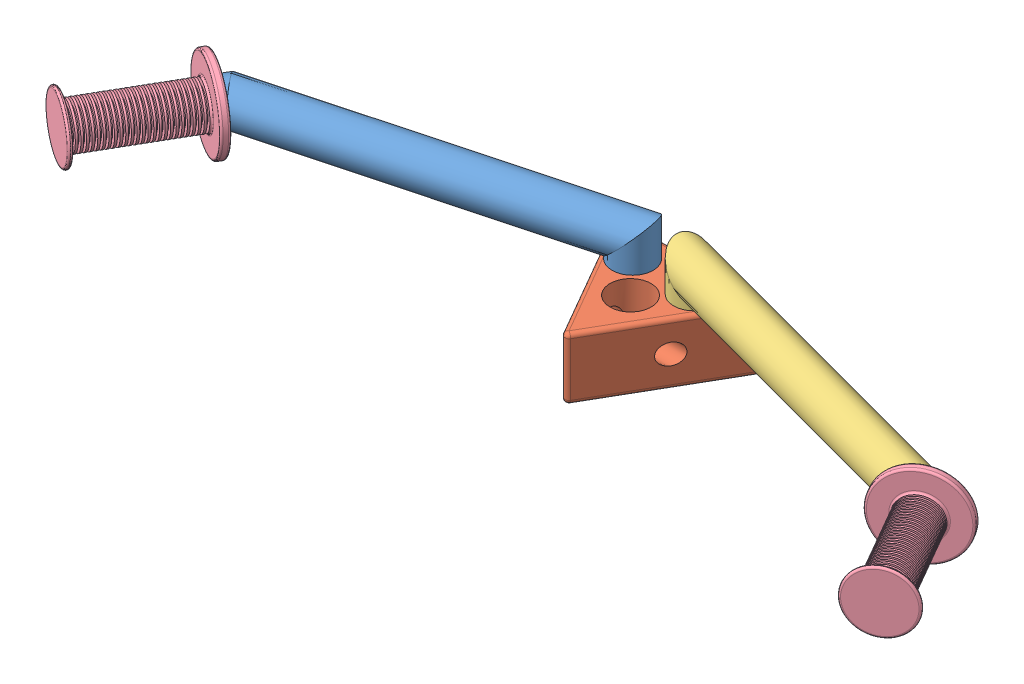
SolidWorks assembly stuur, configuration Default. Lengths in mm.
Overall size (435.74 60.06 120.1).
5 component instances, 4 part files, 8 mates.
Components (placement in the parent):
- stuurbuis1-2: stuurbuis1 [Default] at (-32.5291 -26.394 40.1826) x (-0.965926 0 0.258819) z (-0.258819 0 -0.965926) size (215.96 50 55.96)
- stuur-tussenstuk-1: stuur-tussenstuk [Default] at (-17.5291 -26.394 90.1345) size (72.07 30.12 62.95)
- stuurbuis2-1: stuurbuis2 [Default] at (-2.5291 -26.394 40.1826) x (0.965926 0 0.258819) z (-0.258819 0 0.965926) size (215.96 50 55.96)
- handvat-1: handvat [Default] at (-189.5772 13.606 85.9238) x (-0.5 0 0.866025) z (-0.866025 0 -0.5) size (57 40 40)
- handvat-2: handvat [Default] at (154.5191 13.606 85.9238) x (0.5 0 0.866025) z (-0.866025 0 0.5) size (57 40 40)
Mates (geometry in assembly coordinates):
- Coincident5: coincident anti-aligned: circle of ?; circle of stuur-tussenstuk-1
- Parallel3: parallel aligned: plane of ? through (170.676 12.0364 140.1826) normal (0.866025 0 0.5); plane of stuur-tussenstuk-1 through (-17.5291 3.606 90.1345) normal (0.866025 0 0.5)
- Coincident6: coincident anti-aligned: circle of stuurbuis1-2; circle of stuur-tussenstuk-1
- Angle2: planar angle = 3.665191 rad aligned: plane of stuurbuis1-2 through (-217.0772 13.606 133.5552) normal (-0.5 0 0.866025); plane of stuur-tussenstuk-1 through (19.9709 3.606 25.1826) normal (0 0 -1)
- Coincident7: coincident aligned: circle of stuur-tussenstuk-1; circle of stuurbuis2-1
- Angle1: planar angle = 3.665191 rad aligned: plane of stuur-tussenstuk-1 through (19.9709 3.606 25.1826) normal (0 0 -1); plane of stuurbuis2-1 through (182.0191 13.606 133.5552) normal (0.5 0 0.866025)
- Coincident9: coincident anti-aligned: circle of stuurbuis1-2; circle of handvat-1
- Coincident10: coincident anti-aligned: circle of stuurbuis2-1; circle of handvat-2
